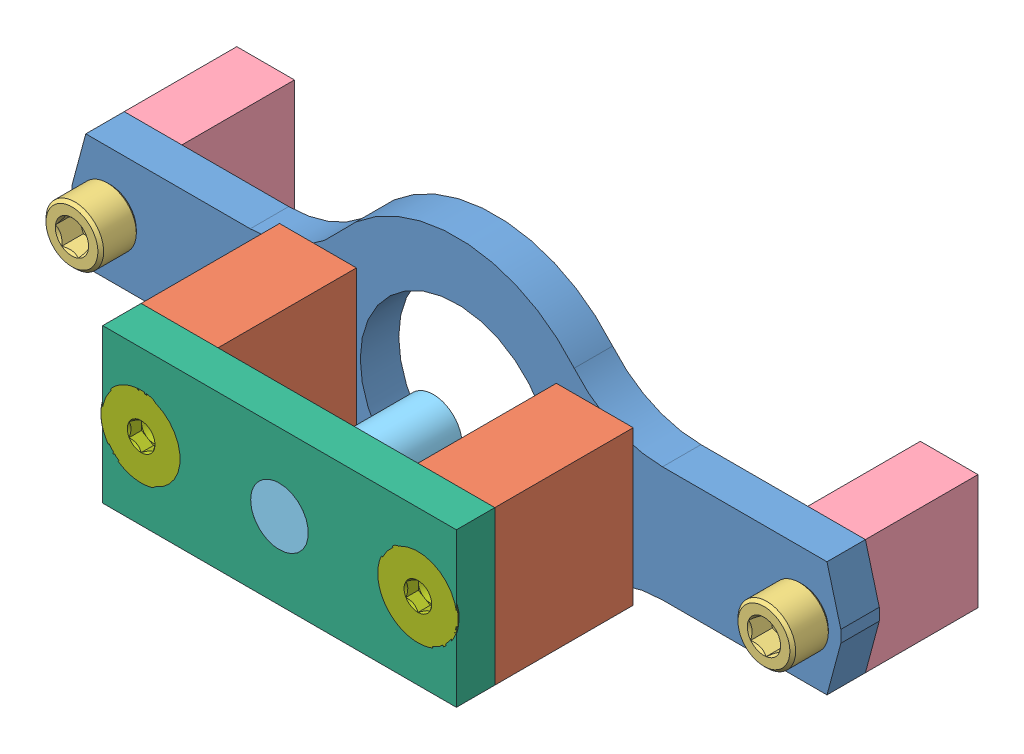
SolidWorks assembly Cesaroni_Pro98_Retainer_Bracket, configuration Default. Lengths in mm.
Overall size (127 50.8 55.98).
11 component instances, 7 part files, 22 mates.
Components (placement in the parent):
- Retainment_Strap-1: Retainment_Strap [Default] at (-59.6607 23.4736 15.5345) size (127 50.8 6.35)
- Motor_Retainer_Standoff-1: Motor_Retainer_Standoff [Default] at (-19.0207 13.9486 21.8845) x (0 -1 0) z (0 0 1) size (25.4 12.7 22.86)
- Motor_Retainer_Standoff-2: Motor_Retainer_Standoff [Default] at (26.6993 13.9486 21.8845) x (0 1 0) z (0 0 1) size (25.4 12.7 22.86)
- 0.25-20_1.0in_Allen Head_Cap_Screw_MC-91251A542-1: 0.25-20_1.0in_Allen Head_Cap_Screw_MC-91251A542 [91251A542] at (60.9893 13.9486 -3.5155) x (0.991655 0.128921 0) z (0 0 -1) size (9.53 9.53 33.14)
- 0.25-20_1.0in_Allen Head_Cap_Screw_MC-91251A542-2: 0.25-20_1.0in_Allen Head_Cap_Screw_MC-91251A542 [91251A542] at (-53.3107 13.9486 -3.5155) x (-0.923728 -0.383049 0) z (0 0 -1) size (9.53 9.53 33.14)
- Cesaroni_Pro98_Retainer_Spacer-1: Cesaroni_Pro98_Retainer_Spacer [Default] at (-52.6122 13.9486 -3.0583) x (0 1 0) z (0 0 1) size (19.05 9.53 18.59)
- Cesaroni_Pro98_Retainer_Spacer-2: Cesaroni_Pro98_Retainer_Spacer [Default] at (60.2908 13.9486 -3.0583) x (0 -1 0) z (0 0 1) size (19.05 9.53 18.59)
- Cesaroni_Pro98_Retaining_Welded_Bolt-1: Cesaroni_Pro98_Retaining_Welded_Bolt [Default] at (3.8393 13.9486 25.6945) size (9.53 9.53 25.4)
- Cesaroni_Pro98_Retaining_CrossBar-1: Cesaroni_Pro98_Retaining_CrossBar [Default] at (33.0493 13.9486 47.9195) x (0 -1 0) z (-1 0 0) size (25.4 6.61 58.42)
- 0.25-20_1.5in_Long_Countersunk_Screw-1: 0.25-20_1.5in_Long_Countersunk_Screw [91253A546] at (26.6993 13.9486 47.0051) size (13.37 13.37 38.38)
- 0.25-20_1.5in_Long_Countersunk_Screw-2: 0.25-20_1.5in_Long_Countersunk_Screw [91253A546] at (-19.0207 13.9486 47.0051) size (13.37 13.37 38.38)
Mates (geometry in assembly coordinates):
- Coincident9: coincident anti-aligned: plane of Retainment_Strap-1 through (3.8393 13.9486 21.8845) normal (0 0 1); plane of Motor_Retainer_Standoff-2 through (20.3493 26.6486 21.8845) normal (0 0 -1)
- Coincident24: coincident anti-aligned: axis of Retainment_Strap-1 through (-53.3107 13.9486 15.5345) axis (0 0 1); axis of 0.25-20_1.0in_Allen Head_Cap_Screw_MC-91251A542-2 through (-53.3107 13.9486 27.7583) axis (0 0 -1)
- Coincident25: coincident anti-aligned: plane of Retainment_Strap-1 through (3.8393 13.9486 21.8845) normal (0 0 1); plane of 0.25-20_1.0in_Allen Head_Cap_Screw_MC-91251A542-2 through (-53.3107 13.9486 21.8845) normal (0 0 -1)
- Coincident26: coincident anti-aligned: axis of Retainment_Strap-1 through (60.9893 13.9486 15.5345) axis (0 0 1); axis of 0.25-20_1.0in_Allen Head_Cap_Screw_MC-91251A542-1 through (60.9893 13.9486 27.7583) axis (0 0 -1)
- Coincident27: coincident anti-aligned: plane of Retainment_Strap-1 through (3.8393 13.9486 21.8845) normal (0 0 1); plane of 0.25-20_1.0in_Allen Head_Cap_Screw_MC-91251A542-1 through (60.9893 13.9486 21.8845) normal (0 0 -1)
- Parallel4: parallel aligned: plane of Retainment_Strap-1 through (-59.6607 23.4736 21.8845) normal (-1 0 0); plane of Cesaroni_Pro98_Retainer_Spacer-1 through (-57.3747 4.4236 15.5345) normal (-1 0 0)
- Coincident39: coincident aligned: axis of Retainment_Strap-1 through (-53.3107 13.9486 15.5345) axis (0 0 1); axis of Cesaroni_Pro98_Retainer_Spacer-1 through (-53.3107 13.9486 0.2945) axis (0 0 1)
- Coincident40: coincident anti-aligned: plane of Retainment_Strap-1 through (3.8393 13.9486 15.5345) normal (0 0 -1); plane of Cesaroni_Pro98_Retainer_Spacer-1 through (-57.3747 23.4736 15.5345) normal (0 0 1)
- Concentric1: concentric anti-aligned: cylinder of 0.25-20_1.0in_Allen Head_Cap_Screw_MC-91251A542-1 through (60.9893 13.9486 28.2345) axis (0 0 -1) radius 4.7625; cylinder of Cesaroni_Pro98_Retainer_Spacer-2 through (60.9893 13.9486 15.5345) axis (0 0 1) radius 3.2639
- Parallel5: parallel aligned: plane of Retainment_Strap-1 through (67.3393 23.4736 21.8845) normal (1 0 0); plane of Cesaroni_Pro98_Retainer_Spacer-2 through (65.0533 23.4736 15.5345) normal (1 0 0)
- Coincident42: coincident anti-aligned: plane of Retainment_Strap-1 through (3.8393 13.9486 15.5345) normal (0 0 -1); plane of Cesaroni_Pro98_Retainer_Spacer-2 through (65.0533 4.4236 15.5345) normal (0 0 1)
- Concentric2: concentric anti-aligned: cylinder of Cesaroni_Pro98_Retaining_Welded_Bolt-1 through (3.8393 13.9486 51.0945) axis (0 0 -1) radius 4.7625; cylinder of Cesaroni_Pro98_Retaining_CrossBar-1 through (3.8393 13.9486 51.0945) axis (0 0 1) radius 4.7625
- Coincident44: coincident aligned: plane of Cesaroni_Pro98_Retaining_Welded_Bolt-1 through (3.8393 13.9486 51.0945) normal (0 0 1); plane of Cesaroni_Pro98_Retaining_CrossBar-1 through (-25.3707 26.6486 51.0945) normal (0 0 1)
- Concentric3: concentric aligned: cylinder of Motor_Retainer_Standoff-2 through (26.6993 13.9486 44.7445) axis (0 0 1) radius 3.3782; cylinder of Cesaroni_Pro98_Retaining_CrossBar-1 through (26.6993 13.9486 51.0945) axis (0 0 1) radius 3.2639
- Concentric4: concentric aligned: cylinder of Motor_Retainer_Standoff-1 through (-19.0207 13.9486 44.7445) axis (0 0 1) radius 3.3782; cylinder of Cesaroni_Pro98_Retaining_CrossBar-1 through (-19.0207 13.9486 51.0945) axis (0 0 1) radius 3.2639
- Concentric5: concentric anti-aligned: cylinder of Retainment_Strap-1 through (26.6993 13.9486 15.5345) axis (0 0 -1) radius 2.5527; cylinder of Motor_Retainer_Standoff-2 through (26.6993 13.9486 44.7445) axis (0 0 1) radius 3.3782
- Concentric6: concentric anti-aligned: cylinder of Retainment_Strap-1 through (-19.0207 13.9486 15.5345) axis (0 0 -1) radius 2.5527; cylinder of Motor_Retainer_Standoff-1 through (-19.0207 13.9486 44.7445) axis (0 0 1) radius 3.3782
- Coincident45: coincident anti-aligned: plane of Motor_Retainer_Standoff-2 through (20.3493 26.6486 44.7445) normal (0 0 1); plane of Cesaroni_Pro98_Retaining_CrossBar-1 through (-25.3707 26.6486 44.7445) normal (0 0 -1)
- Concentric7: concentric anti-aligned: circle of Cesaroni_Pro98_Retaining_CrossBar-1; circle of 0.25-20_1.5in_Long_Countersunk_Screw-1
- Coincident47: coincident aligned: plane of Cesaroni_Pro98_Retaining_CrossBar-1 through (-25.3707 26.6486 51.0945) normal (0 0 1); plane of 0.25-20_1.5in_Long_Countersunk_Screw-1 through (26.6993 13.9486 51.0945) normal (0 0 1)
- Coincident50: coincident aligned: plane of Cesaroni_Pro98_Retaining_CrossBar-1 through (-25.3707 26.6486 51.0945) normal (0 0 1); plane of 0.25-20_1.5in_Long_Countersunk_Screw-2 through (-19.0207 13.9486 51.0945) normal (0 0 1)
- Concentric8: concentric aligned: circle of Cesaroni_Pro98_Retaining_CrossBar-1; circle of 0.25-20_1.5in_Long_Countersunk_Screw-2
